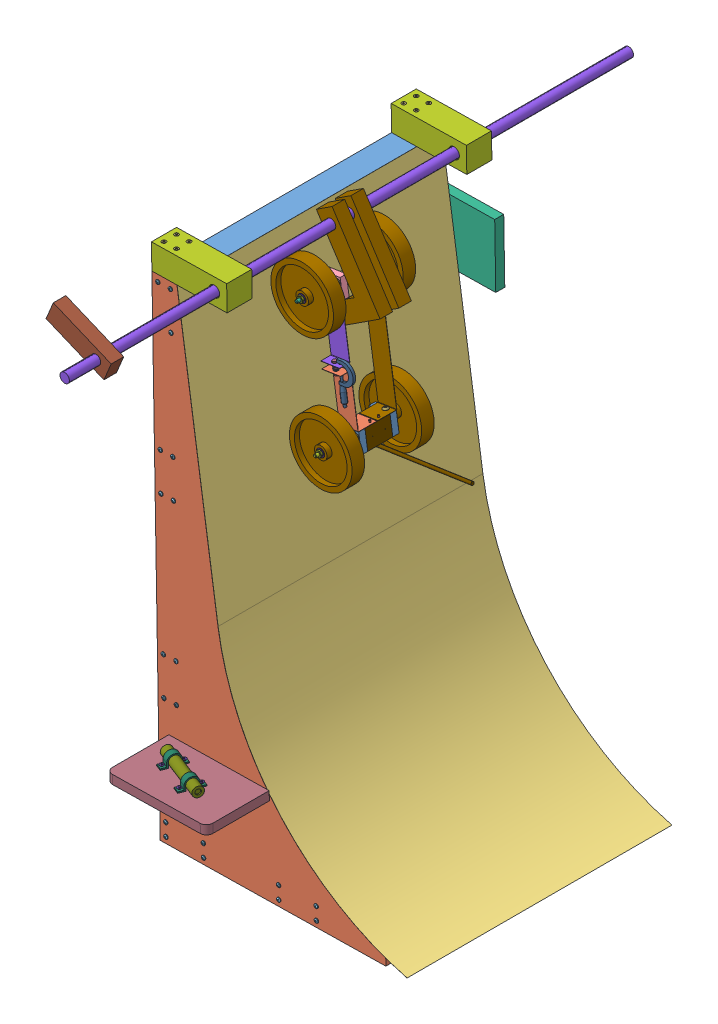
SolidWorks assembly Ramp and Car, configuration Default. Lengths in mm.
Overall size (518.53 1077.79 1143).
157 component instances, 52 part files, 4 mates.
Components (placement in the parent):
- Ramp System-1: Ramp System [Default] at (76.7428 42.7853 84.7967) size (518.53 1077.79 1143)
  - Ramp-1: Ramp [Default] at (68.598 121.8193 472.884) size (517.11 999.07 560.24)
    - base support-1: base support [Default] at (50.3599 26.2618 18.2563) x (0.999855 0.017038 0) z (0 0 1) size (101.6 50.8 500)
    - base support-2: base support [Default] at (278.9267 30.1567 18.2563) x (0.999855 0.017038 0) z (0 0 1) size (101.6 50.8 500)
    - base support-3: base support [Default] at (9.3841 940.0963 18.2563) x (0.017038 -0.999855 0) z (0 0 1) size (101.6 50.8 500)
    - base support-4: base support [Default] at (14.3609 648.0387 18.2563) x (-0.017038 0.999855 0) z (0 0 1) size (101.6 50.8 500)
    - base support-5: base support [Default] at (20.4196 292.4904 18.2563) x (-0.017038 0.999855 0) z (0 0 1) size (101.6 50.8 500)
    - Ramp Right Side-2: Ramp Right Side [Default] at (0 0 518.2563) x (0.999855 0.017038 0) z (0 0 1) size (457.2 990.6 18.26)
    - ramp top-2: ramp top [Default] at (72.1988 -109.1723 0.0645) x (0.999855 0.017038 0) z (0 0 1) size (449.5 990.69 536.45)
    - Left Ramp Side-1: Left Ramp Side [Default] x (0.999855 0.017038 0) z (0 0 1) size (457.2 990.6 18.26)
    - Smaller Wood Screw-1: Smaller Wood Screw [93360A255] at (12.049 38.3109 517.4625) x (0 0 -1) z (0.99986 0.016723 0) size (40.83 7.98 7.98)
    - Smaller Wood Screw-2: Smaller Wood Screw [93360A255] at (88.238 39.6091 517.4625) x (0 0 -1) z (0.737932 -0.674875 0) size (40.83 7.98 7.98)
    - Smaller Wood Screw-3: Smaller Wood Screw [93360A255] at (12.4818 12.9145 517.4625) x (0 0 -1) z (0.728347 -0.685209 0) size (40.83 7.98 7.98)
    - Smaller Wood Screw-4: Smaller Wood Screw [93360A255] at (88.6707 14.2128 517.4625) x (0 0 -1) z (0.978218 -0.207583 0) size (40.83 7.98 7.98)
    - Smaller Wood Screw-5: Smaller Wood Screw [93360A255] at (240.6158 42.2057 517.4625) x (0 0 -1) z (0.895633 -0.444794 0) size (40.83 7.98 7.98)
    - Smaller Wood Screw-6: Smaller Wood Screw [93360A255] at (317.2375 18.1077 517.4625) x (0 0 -1) z (0.927956 -0.37269 0) size (40.83 7.98 7.98)
    - Smaller Wood Screw-7: Smaller Wood Screw [93360A255] at (241.0486 16.8094 517.4625) x (0 0 -1) z (0.947454 -0.319891 0) size (40.83 7.98 7.98)
    - Smaller Wood Screw-8: Smaller Wood Screw [93360A255] at (316.8048 43.504 517.4625) x (0 0 -1) z (0.916674 -0.399636 0) size (40.83 7.98 7.98)
    - Smaller Wood Screw-9: Smaller Wood Screw [93360A255] at (27.7082 610.1607 517.4625) x (0 0 -1) z (-0.434402 -0.900719 0) size (40.83 7.98 7.98)
    - Smaller Wood Screw-10: Smaller Wood Screw [93360A255] at (8.3705 254.1795 517.4625) x (0 0 -1) z (0.029195 -0.999574 0) size (40.83 7.98 7.98)
    - Smaller Wood Screw-11: Smaller Wood Screw [93360A255] at (2.3119 609.7279 517.4625) x (0 0 -1) z (-0.383207 -0.923662 0) size (40.83 7.98 7.98)
    - Smaller Wood Screw-12: Smaller Wood Screw [93360A255] at (33.7669 254.6123 517.4625) x (0 0 -1) z (-0.101676 -0.994818 0) size (40.83 7.98 7.98)
    - Smaller Wood Screw-13: Smaller Wood Screw [93360A255] at (32.4686 330.8012 517.0434) x (0 0 -1) z (0.798033 -0.602614 0) size (40.83 7.98 7.98)
    - Smaller Wood Screw-14: Smaller Wood Screw [93360A255] at (7.0723 330.3685 517.4625) x (0 0 -1) z (0.916528 -0.39997 0) size (40.83 7.98 7.98)
    - Smaller Wood Screw-15: Smaller Wood Screw [93360A255] at (22.7314 902.2183 517.4625) x (0 0 -1) z (0.94297 -0.332878 0) size (40.83 7.98 7.98)
    - Smaller Wood Screw-16: Smaller Wood Screw [93360A255] at (21.4332 978.4072 517.4625) x (0 0 -1) z (0.957808 -0.287409 0) size (40.83 7.98 7.98)
    - Smaller Wood Screw-17: Smaller Wood Screw [93360A255] at (26.4099 686.3496 517.4625) x (0 0 -1) z (0.9364 -0.350934 0) size (40.83 7.98 7.98)
    - Smaller Wood Screw-18: Smaller Wood Screw [93360A255] at (-2.6649 901.7855 517.4625) x (0 0 -1) z (0.929454 -0.368937 0) size (40.83 7.98 7.98)
    - Smaller Wood Screw-19: Smaller Wood Screw [93360A255] at (-3.9632 977.9744 517.4625) x (0 0 -1) z (0.716357 -0.697734 0) size (40.83 7.98 7.98)
    - Smaller Wood Screw-20: Smaller Wood Screw [93360A255] at (1.0136 685.9168 517.4625) x (0 0 -1) z (0.980156 -0.198228 0) size (40.83 7.98 7.98)
    - Smaller Wood Screw-21: Smaller Wood Screw [93360A255] at (21.4332 978.4072 19.05) x (0 0 1) z (-0.976976 0.213347 0) size (40.83 7.98 7.98)
    - Smaller Wood Screw-22: Smaller Wood Screw [93360A255] at (-2.6649 901.7855 19.05) x (0 0 1) z (-0.975802 0.218657 0) size (40.83 7.98 7.98)
    - Smaller Wood Screw-23: Smaller Wood Screw [93360A255] at (-3.9632 977.9744 19.05) x (0 0 1) z (-0.973932 0.22684 0) size (40.83 7.98 7.98)
    - Smaller Wood Screw-24: Smaller Wood Screw [93360A255] at (22.7314 902.2183 19.05) x (0 0 1) z (-0.980702 0.195508 0) size (40.83 7.98 7.98)
    - Smaller Wood Screw-25: Smaller Wood Screw [93360A255] at (1.0136 685.9168 19.05) x (0 0 1) z (-0.999462 -0.032793 0) size (40.83 7.98 7.98)
    - Smaller Wood Screw-26: Smaller Wood Screw [93360A255] at (2.3119 609.7279 19.05) x (0 0 1) z (-0.993805 0.11114 0) size (40.83 7.98 7.98)
    - Smaller Wood Screw-27: Smaller Wood Screw [93360A255] at (26.4099 686.3496 19.05) x (0 0 1) z (-0.996065 0.088627 0) size (40.83 7.98 7.98)
    - Smaller Wood Screw-28: Smaller Wood Screw [93360A255] at (27.7082 610.1607 19.05) x (0 0 1) z (-0.990107 0.140311 0) size (40.83 7.98 7.98)
    - Smaller Wood Screw-29: Smaller Wood Screw [93360A255] at (32.4686 330.8012 19.05) x (0 0 1) z (-0.984191 0.177108 0) size (40.83 7.98 7.98)
    - Smaller Wood Screw-30: Smaller Wood Screw [93360A255] at (8.3705 254.1795 19.05) x (0 0 1) z (-0.989085 0.147348 0) size (40.83 7.98 7.98)
    - Smaller Wood Screw-31: Smaller Wood Screw [93360A255] at (7.0723 330.3685 19.05) x (0 0 1) z (-0.990343 0.138636 0) size (40.83 7.98 7.98)
    - Smaller Wood Screw-32: Smaller Wood Screw [93360A255] at (33.7669 254.6123 19.05) x (0 0 1) z (-0.990372 0.138429 0) size (40.83 7.98 7.98)
    - Smaller Wood Screw-33: Smaller Wood Screw [93360A255] at (12.049 38.3109 19.05) x (0 0 1) z (-0.99641 0.084662 0) size (40.83 7.98 7.98)
    - Smaller Wood Screw-34: Smaller Wood Screw [93360A255] at (12.4818 12.9145 19.05) x (0 0 1) z (-0.902798 0.430064 0) size (40.83 7.98 7.98)
    - Smaller Wood Screw-35: Smaller Wood Screw [93360A255] at (88.238 39.6091 19.05) x (0 0 1) z (-0.346699 0.937977 0) size (40.83 7.98 7.98)
    - Smaller Wood Screw-36: Smaller Wood Screw [93360A255] at (88.6707 14.2128 19.05) x (0 0 1) z (-0.822189 0.569215 0) size (40.83 7.98 7.98)
    - Smaller Wood Screw-37: Smaller Wood Screw [93360A255] at (241.0486 16.8094 19.05) x (0 0 1) z (-0.485074 0.874473 0) size (40.83 7.98 7.98)
    - Smaller Wood Screw-38: Smaller Wood Screw [93360A255] at (316.8048 43.504 19.05) x (0 0 1) z (0.344552 0.938767 0) size (40.83 7.98 7.98)
    - Smaller Wood Screw-39: Smaller Wood Screw [93360A255] at (317.2375 18.1077 19.05) x (0 0 1) z (-0.659807 0.751435 0) size (40.83 7.98 7.98)
    - Smaller Wood Screw-40: Smaller Wood Screw [93360A255] at (240.6158 42.2057 19.05) x (0 0 1) z (-0.848855 0.528626 0) size (40.83 7.98 7.98)
    - Position Marker-1: Position Marker [Default] at (14.1597 889.3708 -18.2626) x (0.017024 -0.999855 0) z (0 0 1) size (127 127 18.26)
    - Smaller Wood Screw-41: Smaller Wood Screw [93360A255] at (39.9884 864.4069 0.7874) x (0 0 1) z (0.509818 0.860282 0) size (40.83 7.98 7.98)
    - Smaller Wood Screw-42: Smaller Wood Screw [93360A255] at (51.3172 788.3888 0.7874) x (0 0 1) z (0.395796 -0.918339 0) size (40.83 7.98 7.98)
  - Release Mechanism-1: Release Mechanism [Default] at (46.9788 1061.4429 877.8659) x (0.999855 0.017038 0) z (0 0 1) size (224.2 244.6 1143)
    - Release support-1: Release support [Default] at (5.6069 50.7445 80.7306) x (0 0 1) z (-1 0 0) size (50.8 50.8 152.4)
    - Release support-2: Release support [Default] at (5.6069 50.7445 -404.9174) x (0 0 1) z (-1 0 0) size (50.8 50.8 152.4)
    - Release Dowel-1: Release Dowel [Default] at (132.6069 76.1445 -708.1934) size (19.05 19.05 1143)
    - RELEASE HOOK-1: RELEASE HOOK [Default] at (102.964 87.5183 -168.4434) x (0.531967 -0.846765 0) z (0 0 1) size (177.8 127 25.4)
    - RELEASE HOOK-2: RELEASE HOOK [Default] at (102.964 87.5183 -130.3434) x (0.531967 -0.846765 0) z (0 0 1) size (177.8 127 25.4)
    - Hook Dowel-1: Hook Dowel [Default] at (133.6443 -80.6855 -171.6184) size (19.05 19.05 69.85)
    - Release Lever-1: Release Lever [Default] at (47.1299 134.2749 345.9066) x (0 0 1) z (0.916371 -0.400331 0) size (25.4 38.1 127)
  - Smaller Wood Screw-1: Smaller Wood Screw [93360A255] at (221.5714 289.9774 991.6165) x (0 0 -1) z (0.43744 -0.899248 0) size (40.83 7.98 7.98)
  - Smaller Wood Screw-2: Smaller Wood Screw [93360A255] at (154.9786 270.425 991.6165) x (0 0 -1) z (0.100324 -0.994955 0) size (40.83 7.98 7.98)
  - Smaller Wood Screw-3: Smaller Wood Screw [93360A255] at (137.2049 288.5398 991.6165) x (0 0 -1) z (0.854567 -0.519342 0) size (40.83 7.98 7.98)
  - Smaller Wood Screw-4: Smaller Wood Screw [93360A255] at (239.3451 271.8626 991.6165) x (0 0 -1) z (-0.232923 -0.972495 0) size (40.83 7.98 7.98)
  - Biggest Wood Screw-1: Biggest Wood Screw [90031A209] at (64.2006 1125.2756 996.6965) x (0.017038 -0.999855 0) z (-0.012431 -0.000212 0.999923) size (76.2 8.43 8.43)
  - Biggest Wood Screw-3: Biggest Wood Screw [90031A209] at (89.5969 1125.7083 511.0485) x (0.017038 -0.999855 0) z (0 0 1) size (76.2 8.43 8.43)
  - Biggest Wood Screw-4: Biggest Wood Screw [90031A209] at (89.5969 1125.7083 485.6485) x (0.017038 -0.999855 0) z (0 0 1) size (76.2 8.43 8.43)
  - Biggest Wood Screw-5: Biggest Wood Screw [90031A209] at (64.2006 1125.2756 485.6485) x (0.017038 -0.999855 0) z (0 0 1) size (76.2 8.43 8.43)
  - Biggest Wood Screw-6: Biggest Wood Screw [90031A209] at (64.2006 1125.2756 511.0485) x (0.017038 -0.999855 0) z (-0.495664 -0.008446 0.868473) size (76.2 8.43 8.43)
  - Biggest Wood Screw-7: Biggest Wood Screw [90031A209] at (89.5969 1125.7083 971.2965) x (0.017038 -0.999855 0) z (0 0 1) size (76.2 8.43 8.43)
  - Biggest Wood Screw-8: Biggest Wood Screw [90031A209] at (89.5969 1125.7083 996.6965) x (0.017038 -0.999855 0) z (0.075008 0.001278 0.997182) size (76.2 8.43 8.43)
  - Biggest Wood Screw-9: Biggest Wood Screw [90031A209] at (64.2006 1125.2756 971.2965) x (0.017038 -0.999855 0) z (0 0 1) size (76.2 8.43 8.43)
  - Assemsight-1: Assemsight [Default] at (228.4786 162.1389 1293.8106) x (-0.999855 -0.017038 0) z (0 0 -1) size (203.2 82.02 127)
    - RampSight-1: RampSight [Default] at (38.0656 138.4152 220.9267) size (203.2 17.78 127)
    - screwangle-1: screwangle [Default] at (-4.0031 138.4152 259.014) x (0 0 -1) z (0 -1 0) size (50.8 34.92 38.1)
    - screwangle-2: screwangle [Default] at (80.3757 138.4152 259.014) x (0 0 -1) z (0 -1 0) size (50.8 34.92 38.1)
    - LaserStrap-3: LaserStrap [Default] at (76.1001 166.1978 233.9353) x (0.37234 0 -0.928096) z (0.928096 0 0.37234) size (45.4 22.54 12.7)
    - LaserStrap-4: LaserStrap [Default] at (17.166 166.1978 210.2918) x (0.37234 0 -0.928096) z (0.928096 0 0.37234) size (45.4 22.54 12.7)
    - laserpointereal-3: laserpointereal [Default] at (-2.9774 166.1952 201.3092) x (-0.371391 0.071332 0.925732) z (0.928096 0 0.37234) size (30.2 30.2 115)
    - Part1^Assemsight-1: Part1^Assemsight [Default] at origin (virtual)
    - Part2^Assemsight-1: Part2^Assemsight [Default] at origin (virtual)
    - sightscrew-1: sightscrew [90031A194] at (16.8102 154.9836 228.2328) x (0 -1 0) z (-0.202266 0 0.979331) size (12.7 8.43 8.43)
    - sightscrew-2: sightscrew [90031A194] at (-12.7344 140.9552 245.9965) x (0 1 0) z (-0.546944 0 0.837169) size (12.7 8.43 8.43)
    - sightscrew-3: sightscrew [90031A194] at (88.8656 154.9836 219.1703) x (0 -1 0) z (-0.546944 0 0.837169) size (12.7 8.43 8.43)
    - sightscrew-4: sightscrew [90031A194] at (4.4741 140.9552 270.7615) x (0 1 0) z (-0.546944 0 0.837169) size (12.7 8.43 8.43)
    - sightscrew-5: sightscrew [90031A194] at (88.8529 140.9552 270.7615) x (0 1 0) z (-0.546944 0 0.837169) size (12.7 8.43 8.43)
    - sightscrew-7: sightscrew [90031A194] at (75.7444 154.9836 251.8764) x (0 -1 0) z (-0.546944 0 0.837169) size (12.7 8.43 8.43)
    - sightscrew-8: sightscrew [90031A194] at (71.6444 140.9552 245.9965) x (0 1 0) z (-0.546944 0 0.837169) size (12.7 8.43 8.43)
    - sightscrew-9: sightscrew [90031A194] at (29.9315 154.9836 195.5267) x (0 -1 0) z (-0.546944 0 0.837169) size (12.7 8.43 8.43)
- Gravity car assembly (Split frame)-1: Gravity car assembly (Split frame) [Default] at (153.1413 842.2114 600.0395) x (0.147399 -0.989077 0) z (0 0 1) size (406.2 298.79 191.04)
  - Front Axle Assembly-2: Front Axle Assembly [Default] at (87.1913 142.031 189.0581) size (164.58 298.79 190.98)
    - Connection Front Suspention-1: Connection Front Suspention [Default] at (-53.6547 15.4423 62.2716) size (38.1 12.7 50.8)
    - suspension front-1: suspension front [Default] at (-72.7047 -21.3877 74.9716) size (38.1 43.18 12.7)
    - suspension front-2: suspension front [Default] at (-72.7047 -21.3877 11.4716) size (38.1 43.18 12.7)
    - Slide Wing Nut-1: Slide Wing Nut [Default] at (-53.6547 8.2033 36.8716) x (0 0 1) z (0 -1 0) size (50.8 6.48 7.05)
    - muffle bearing-1: muffle bearing [Default] at (-53.6547 -6.1477 -1.2284) size (8 8 7)
    - muffle bearing-2: muffle bearing [Default] at (-53.6547 -6.1477 67.9716) size (8 8 7)
    - Threaded Axle Front Left-1: Threaded Axle Front Left [Default] at (-53.6547 -6.1477 83.7836) x (0.967821 0.251639 0) z (0 0 1) size (6.35 6.35 135.47)
    - Adapter One-Way-Bearing-1: Adapter One-Way-Bearing [Default] at (-53.6547 -6.1477 74.9716) x (-0.990269 0.139163 0) z (0 0 -1) size (45 45 20.32)
    - Muffle One-Way-Bearing-1: Muffle One-Way-Bearing [Default] at (-53.6547 -6.1477 84.2916) size (15 15 11)
    - Threaded Axle Front Right-1: Threaded Axle Front Right [Default] at (-53.6547 -6.1477 139.2916) x (0.848775 -0.528754 0) z (0 0 1) size (6.35 6.35 55)
    - muffle wheel right-1: muffle wheel right [Default] at (-53.6547 -6.1477 95.2916) x (0.552032 0.833823 0) z (0 0 1) size (7.94 7.94 31.75)
    - Wheel-1: Wheel [Default] at (-53.6547 -6.1477 114.3416) x (0.992874 0.119172 0) z (0 0 1) size (127 127 25.4)
    - muffle wheel left-1: muffle wheel left [Default] at (-53.6547 -6.1477 -39.3284) size (7.94 7.94 38.1)
    - Wheel-2: Wheel [Default] at (-53.6547 -6.1477 -26.6284) x (-0.36486 0.931062 0) z (0 0 1) size (127 127 25.4)
    - Wingnut-1: Wingnut [Default] at (-63.224 -102.9399 -69.9379) x (0 -1 0) z (0 0 1) size (25.24 12.25 6.43)
    - Button Head Hex Drive Screw 1-4-28-1: Button Head Hex Drive Screw 1-4-28 [Default] at (7.3275 5.2304 29.6861) size (11.1 11.1 16.71)
    - Button Head Hex Drive Screw 1-4-28-2: Button Head Hex Drive Screw 1-4-28 [Default] at (-21.1014 44.8149 44.057) x (0.919454 0.393198 0) z (0 0 -1) size (11.1 11.1 16.71)
    - Button Head Hex Drive Screw 1-4-28-3: Button Head Hex Drive Screw 1-4-28 [Default] at (-19.8729 61.5855 44.057) x (0.622111 0.782929 0) z (0 0 -1) size (11.1 11.1 16.71)
    - Button Head Hex Drive Screw 1-4-28-4: Button Head Hex Drive Screw 1-4-28 [Default] at (-12.9925 5.2304 29.6861) size (11.1 11.1 16.71)
    - Button Head Hex Drive Screw 1-64-1: Button Head Hex Drive Screw 1-64 [Default] at (-66.0699 34.9913 37.8914) x (-0.998887 0 -0.047164) z (0 -1 0) size (3.28 3.28 7.41)
    - Button Head Hex Drive Screw 1-64-2: Button Head Hex Drive Screw 1-64 [Default] at (-37.2671 34.9913 19.4802) x (0.551582 0 -0.83412) z (0 -1 0) size (3.28 3.28 7.41)
    - 608 Ball Bearing-1: 608 Ball Bearing [Default] at (-39.5024 -7.5493 -10.4793) size (22 22 7)
    - 608 Ball Bearing-2: 608 Ball Bearing [Default] at (-39.5024 -7.5493 58.7207) size (22 22 7)
    - One-Way-Bearing-1: One-Way-Bearing [Default] at (-39.7809 -11.9333 83.3481) x (0.996606 0.082318 0) z (0 0 1) size (35 35 11)
    - Stainless Steel Thin Hex Nut 1-4-28-1: Stainless Steel Thin Hex Nut 1-4-28 [Default] at (-18.3908 36.8704 -65.2317) x (0.923728 0.383049 0) z (0.383049 -0.923728 0) size (11.11 4.67 12.83)
    - Stainless Steel Thin Hex Nut 1-4-28-3: Stainless Steel Thin Hex Nut 1-4-28 [Default] at (-4.6024 -32.3769 152.9449) x (1 0 0) z (0 1 0) size (11.11 4.67 12.83)
    - Stainless Steel Thin Hex Nut 1-4-28-4: Stainless Steel Thin Hex Nut 1-4-28 [Default] at (-4.6024 -32.3769 88.8139) x (1 0 0) z (0 1 0) size (11.11 4.67 12.83)
    - 316 Stainless Steel Washer-1: 316 Stainless Steel Washer [Default] at (-18.7651 29.0423 -40.1203) x (1 0 0) z (0 -1 0) size (15.87 1.09 15.87)
    - 316 Stainless Steel Washer-2: 316 Stainless Steel Washer [Default] at (-18.7651 -41.3376 127.8334) x (1 0 0) z (0 1 0) size (15.87 1.09 15.87)
    - Wooden Rod-1: Wooden Rod [Default] at (-31.4297 -59.6477 36.8716) x (-0.156429 0 -0.987689) z (0 1 0) size (6.35 6.35 270)
    - Compression Spring Break-1: Compression Spring Break [Default] at (-95.3507 -1.2922 45.8268) x (-0.627574 0.778557 0) z (0.778557 0.627574 0) size (7.88 17.75 8)
  - Frame 1 Front-1: Frame 1 Front [Default] at (52.12 125.7234 264.7663) x (0 1 0) z (0 0 -1) size (38.1 102.07 59.31)
  - rear axle assembly-2: rear axle assembly [Default] at (-186.4327 107.1435 309.604) x (-1 0 0) z (0 0 -1) size (137.94 137.94 191.03)
    - Connection Rear Suspention-1: Connection Rear Suspention [Default] at (34.964 50.3299 109.0743) size (38.1 12.7 50.8)
    - suspension rear-1: suspension rear [Default] at (15.914 13.4999 121.7743) size (38.1 43.18 12.7)
    - suspension rear-3: suspension rear [Default] at (15.914 13.4999 58.2743) size (38.1 43.18 12.7)
    - threaded axle rear left-1: threaded axle rear left [Default] at (34.964 28.7399 172.2163) x (0.913913 -0.405911 0) z (0 0 1) size (6.35 6.35 63.14)
    - threaded axle rear right-1: threaded axle rear right [Default] at (34.964 28.7399 58.2743) x (0.899499 -0.436922 0) z (0 0 1) size (6.35 6.35 77.09)
    - muffle rear wheels-1: muffle rear wheels [Default] at (34.964 28.7399 25.2543) x (-0.147836 -0.989012 0) z (0 0 -1) size (25.4 25.4 31.75)
    - muffle rear wheels-2: muffle rear wheels [Default] at (34.964 28.7399 128.1243) x (0.995012 -0.099759 0) z (0 0 1) size (25.4 25.4 31.75)
    - Wheel-1: Wheel [Default] at (34.964 28.7399 147.1743) x (-0.032877 -0.999459 0) z (0 0 1) size (127 127 25.4)
    - Wheel-2: Wheel [Default] at (34.964 28.7399 6.2043) x (-0.090252 -0.995919 0) z (0 0 1) size (127 127 25.4)
    - Button Head Hex Drive Screw 1-4-28-1: Button Head Hex Drive Screw 1-4-28 [Default] at (95.9461 40.1179 76.4889) size (11.1 11.1 16.71)
    - Button Head Hex Drive Screw 1-4-28-2: Button Head Hex Drive Screw 1-4-28 [Default] at (75.6261 40.1179 76.4889) size (11.1 11.1 16.71)
    - Button Head Hex Drive Screw 1-4-28-3: Button Head Hex Drive Screw 1-4-28 [Default] at (25.1415 2.4981 90.8598) x (-0.559698 -0.828696 0) z (0 0 -1) size (11.1 11.1 16.71)
    - Button Head Hex Drive Screw 1-4-28-4: Button Head Hex Drive Screw 1-4-28 [Default] at (27.966 -1.4116 90.8598) x (-0.136827 -0.990595 0) z (0 0 -1) size (11.1 11.1 16.71)
    - 316 Stainless Steel Washer-1: 316 Stainless Steel Washer [Default] at (69.8536 -6.45 -6.796) x (1 0 0) z (0 1 0) size (15.87 1.09 15.87)
    - Stainless Steel Thin Hex Nut 1-4-28-1: Stainless Steel Thin Hex Nut 1-4-28 [Default] at (79.493 -4.5958 13.2545) x (0.988533 -0.151006 0) z (0.151006 0.988533 0) size (11.11 4.67 12.83)
    - Stainless Steel Thin Hex Nut 1-4-28-2: Stainless Steel Thin Hex Nut 1-4-28 [Default] at (84.0162 2.5107 50.0655) x (1 0 0) z (0 1 0) size (11.11 4.67 12.83)
    - Stainless Steel Thin Hex Nut 1-4-28-3: Stainless Steel Thin Hex Nut 1-4-28 [Default] at (89.5431 39.474 140.1242) x (0.956264 -0.292503 0) z (-0.292503 -0.956264 0) size (11.11 4.67 12.83)
    - Stainless Steel Thin Hex Nut 1-4-28-4: Stainless Steel Thin Hex Nut 1-4-28 [Default] at (84.0162 54.9691 103.3132) x (1 0 0) z (0 -1 0) size (11.11 4.67 12.83)
    - 316 Stainless Steel Washer-2: 316 Stainless Steel Washer [Default] at (69.8536 -6.45 160.6662) x (1 0 0) z (0 1 0) size (15.87 1.09 15.87)
  - Frame 1 Rear-1: Frame 1 Rear [Default] at (-239.98 163.8234 264.7663) x (0 -1 0) z (0 0 -1) size (38.1 102.07 59.31)
  - Frame 2-1: Frame 2 [Default] at (-93.93 144.7734 187.0931) x (0 -1 0) z (0 0 1) size (38.1 216.83 38.57)
  - micrometer-1: micrometer [Default] at (-87.072 154.5295 275.8595) size (79.21 32.22 9.73)
  - Dovel Pin-1: Dovel Pin [Default] at (-180.8731 155.7714 214.5027) size (9.53 3.17 3.17)
  - Dovel Pin-2: Dovel Pin [Default] at (36.8755 155.7714 214.5027) size (9.53 3.17 3.17)
  - Dovel Pin-3: Dovel Pin [Default] at (37.0749 156.6444 196.6684) x (1 0 0) z (0 -0.042895 0.99908) size (9.53 3.17 3.17)
  - Dovel Pin-4: Dovel Pin [Default] at (-180.6606 159.7623 196.7804) x (1 0 0) z (0 -0.194828 0.980837) size (9.53 3.17 3.17)
  - Button Head Hex Drive Screw-1: Button Head Hex Drive Screw [Default] at (-222.5435 144.9102 278.0185) x (0 -0.37422 0.92734) z (1 0 0) size (11.1 11.1 16.71)
  - Button Head Hex Drive Screw-2: Button Head Hex Drive Screw [Default] at (-222.5435 155.4902 174.7001) x (0 0.518952 -0.854804) z (1 0 0) size (11.1 11.1 16.71)
  - Button Head Hex Drive Screw-3: Button Head Hex Drive Screw [Default] at (34.6834 149.1415 214.8399) x (0 0.229818 0.973234) z (-1 0 0) size (11.1 11.1 16.71)
  - Button Head Hex Drive Screw-4: Button Head Hex Drive Screw [Default] at (35.137 166.9672 248.2355) x (0 0.777919 -0.628364) z (-1 0 0) size (11.1 11.1 16.71)
  - Clevis Pin-1: Clevis Pin [Default] at (-74.1199 148.1369 260.5172) x (0 0.193544 -0.981092) z (-1 0 0) size (9.65 9.65 24.77)
  - Compression Spring-1: Compression Spring [Default] at (-107.1337 156.2016 259.2559) x (0 0.59115 -0.806562) z (1 0 0) size (9.45 9.58 13.23)
Mates (geometry in assembly coordinates):
- Tangent1: tangent: plane of Ramp System-1/Ramp-1/ramp top-2 through (179.5571 1156.0261 1094.1932) normal (0.989077 0.147399 0); cylinder of Gravity car assembly (Split frame)-1/rear axle assembly-2/Wheel-2 through (253.6649 1089.5514 916.1392) axis (0 0 -1) radius 63.5
- Tangent2: tangent: plane of Ramp System-1/Ramp-1/ramp top-2 through (179.5571 1156.0261 1094.1932) normal (0.989077 0.147399 0); cylinder of Gravity car assembly (Split frame)-1/Front Axle Assembly-2/Wheel-1 through (291.2419 837.4028 890.7392) axis (0 0 1) radius 63.5
- Width3: width: plane of Ramp System-1/Release Mechanism-1/Hook Dowel-1 through (258.7212 1025.8314 860.8942) normal (0 0 1); plane of Ramp System-1/Release Mechanism-1/Hook Dowel-1 through (258.7212 1025.8314 791.0442) normal (0 0 -1); plane of Gravity car assembly (Split frame)-1/Frame 1 Rear-1 through (278.5605 1112.0502 864.8058) normal (0 0 -1); plane of Gravity car assembly (Split frame)-1/Frame 2-1 through (281.2463 964.7875 787.1326) normal (0 0 1)
- Coincident4: coincident: plane of Ramp System-1/Release Mechanism-1/RELEASE HOOK-1 through (301.5001 1076.4784 819.6192) normal (-0.546317 0.837578 0); line of Gravity car assembly (Split frame)-1/Frame 2-1 through (285.4243 1065.9929 787.8692) axis (0 0 1)
